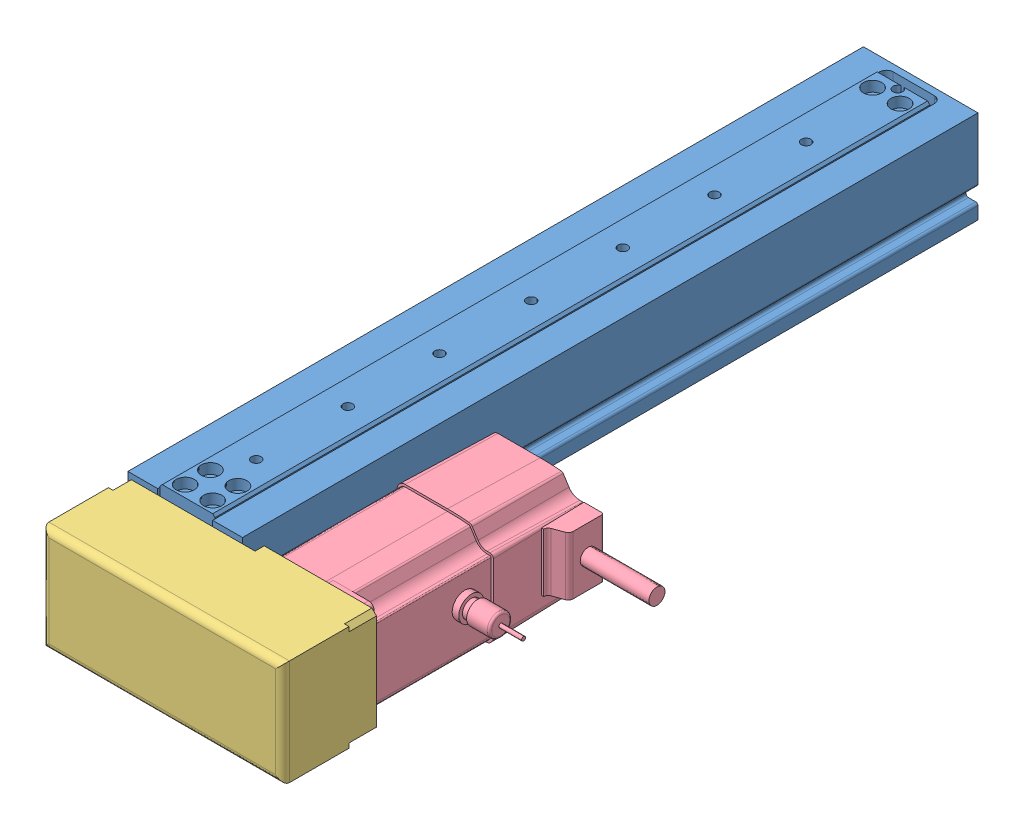
SolidWorks assembly S5M-BR-100W, configuration 默认. Lengths in mm.
Overall size (150.7 54 358).
7 component instances, 5 part files, 23 mates.
Components (placement in the parent):
- S5-BL-导轨^S5M-BR-100W-1: S5-BL-导轨^S5M-BR-100W [默认] x (-1 0 0) z (0 0 -1) size (50 42.7 321) (virtual)
- 传感器^S5M-BR-100W-3: 传感器^S5M-BR-100W [默认] at (-31.75 -24.6 -263) x (-1 0 0) z (0 0 -1) size (13.5 27.2 26.1) (virtual)
- 传感器^S5M-BR-100W-5: 传感器^S5M-BR-100W [默认] at (-31.75 -24.6 -45) x (-1 0 0) z (0 0 -1) size (13.5 27.2 26.1) (virtual)
- 传感器^S5M-BR-100W-6: 传感器^S5M-BR-100W [默认] at (-31.75 -24.6 -71.1) x (-1 0 0) z (0 0 -1) size (13.5 27.2 26.1) (virtual)
- S5-BL-42M电机安装板^S5M-BR-100W-1: S5-BL-42M电机安装板^S5M-BR-100W [默认] at (27 -18.4 -3) x (-1 0 0) z (0 0 1) size (105 46 41) (virtual)
- 100W 电机^S5M-BR-100W-1: 100W 电机^S5M-BR-100W [默认] at (53.5 -18.4 -59) x (0 -1 0) z (0 0 -1) size (42.54 79.97 121.5) (virtual)
- S5-BC-滑块组件^S5M-BR-100W-1: S5-BC-滑块组件^S5M-BR-100W [Default] at (-16.8713 -4.7727 -107.9113) x (-1 0 0) z (0 0 1) size (57.33 40 73.16) (virtual)
Mates (geometry in assembly coordinates):
- 重合144: coincident: plane of 传感器^S5M-BR-100W-3 through (-25 -35.7 -269.3) normal (0 -1 0); plane of 传感器^S5M-BR-100W-6 through (-25 -35.7 -77.4) normal (0 -1 0)
- 重合148: coincident: plane of 传感器^S5M-BR-100W-6 through (-25 -35.7 -77.4) normal (0 -1 0); plane of 传感器^S5M-BR-100W-5 through (-25 -35.7 -51.3) normal (0 -1 0)
- 距离28: distance = 19.8 mm: plane of 传感器^S5M-BR-100W-6 through (-38.5 -13.5 -71.1) normal (0 0 1); plane of 传感器^S5M-BR-100W-5 through (-38.5 -13.5 -51.3) normal (0 0 -1)
- 同心299: concentric: cylinder of S5-BL-42M电机安装板^S5M-BR-100W-1 through (53.5 -18.4 -11) axis (0 0 1) radius 8; cylinder of 100W 电机^S5M-BR-100W-1 through (53.5 -18.4 -3) axis (0 0 1) radius 4
- 重合176: coincident: plane of S5-BL-42M电机安装板^S5M-BR-100W-1 through (-25.5 -41.4 -3) normal (0 0 -1); plane of 100W 电机^S5M-BR-100W-1 through (53.5086 -18.3803 -3) normal (0 0 1)
- 平行1: parallel: plane of S5-BL-42M电机安装板^S5M-BR-100W-1 through (79.5 4.6 9) normal (1 0 0); plane of 100W 电机^S5M-BR-100W-1 through (73.5 -6.3 -59) normal (1 0 0)
- 重合177: coincident: plane of S5-BL-42M电机安装板^S5M-BR-100W-1 through (-54.4225 14.0778 1) normal (0 0 -1); plane of S5-BL-导轨^S5M-BR-100W-1 through (0 0 1) normal (0 0 1)
- 平行5: parallel: plane of S5-BL-42M电机安装板^S5M-BR-100W-1 through (79.5 -41.4 9) normal (0 -1 0); plane of S5-BL-导轨^S5M-BR-100W-1 through (25 7 -10) normal (0 1 0)
- 距离29: distance = 25 mm: plane of S5-BC-滑块组件^S5M-BR-100W-1; plane of S5-BL-导轨^S5M-BR-100W-1 through (-25 7 -10) normal (-1 0 0)
- 距离30: distance = 54 mm: plane of S5-BC-滑块组件^S5M-BR-100W-1 through (-21 -45.5 -75.9113) normal (0 -1 0); plane of S5-BL-导轨^S5M-BR-100W-1 through (12 8.5 -312) normal (0 1 0)
- 重合188: coincident: plane of 传感器^S5M-BR-100W-3 through (-25 -35.7 -269.3) normal (1 0 0); plane of 传感器^S5M-BR-100W-5 through (-25 -35.7 -51.3) normal (1 0 0)
- 重合189: coincident: plane of 传感器^S5M-BR-100W-5 through (-25 -35.7 -51.3) normal (1 0 0); plane of 传感器^S5M-BR-100W-6 through (-25 -35.7 -77.4) normal (1 0 0)
- 重合190: coincident: plane of 传感器^S5M-BR-100W-5 through (-25 -13.5 -51.3) normal (0 1 0); plane of 传感器^S5M-BR-100W-6 through (-25 -13.5 -77.4) normal (0 1 0)
- 重合191: coincident: plane of 传感器^S5M-BR-100W-3 through (-25 -13.5 -269.3) normal (0 1 0); plane of 传感器^S5M-BR-100W-6 through (-25 -13.5 -77.4) normal (0 1 0)
- 重合192: coincident: plane of 传感器^S5M-BR-100W-3 through (-25 -35.7 -269.3) normal (1 0 0); plane of S5-BL-导轨^S5M-BR-100W-1 through (-25 7 -10) normal (-1 0 0)
- 距离35: distance = 22 mm: plane of 传感器^S5M-BR-100W-3 through (-25 -13.5 -269.3) normal (0 1 0); plane of S5-BL-导轨^S5M-BR-100W-1 through (12 8.5 -312) normal (0 1 0)
- 距离37: distance = 40.8 mm: plane of 传感器^S5M-BR-100W-3 through (-28 -16.7 -279.2) normal (0 0 -1); plane of S5-BL-导轨^S5M-BR-100W-1 through (0 0 -320) normal (0 0 -1)
- 距离39: distance = 0.5 mm: plane of S5-BL-导轨^S5M-BR-100W-1 through (-25 7 -10) normal (-1 0 0); plane of S5-BL-42M电机安装板^S5M-BR-100W-1 through (-25.5 4.6 9) normal (-1 0 0)
- 距离40: distance = 7.2 mm: plane of S5-BL-导轨^S5M-BR-100W-1 through (-12.5 -34.2 -8) normal (0 -1 0); plane of S5-BL-42M电机安装板^S5M-BR-100W-1 through (79.5 -41.4 9) normal (0 -1 0)
- 距离41: distance = 73.1 mm: plane of 传感器^S5M-BR-100W-5 through (-28 -16.7 -35.1) normal (0 0 1); plane of S5-BL-42M电机安装板^S5M-BR-100W-1 through (27 -18.4 38) normal (0 0 1)
- 重合193: coincident: plane of S5-BL-导轨^S5M-BR-100W-1 through (0 0 0) normal (-1 0 0); plane of assembly through (0 0 0) normal (1 0 0)
- 重合194: coincident: plane of S5-BL-导轨^S5M-BR-100W-1; plane of assembly through (0 0 0) normal (0 1 0)
- 重合195: coincident: plane of S5-BL-导轨^S5M-BR-100W-1 through (0 0 0) normal (0 0 -1); plane of assembly through (0 0 0) normal (0 0 1)
